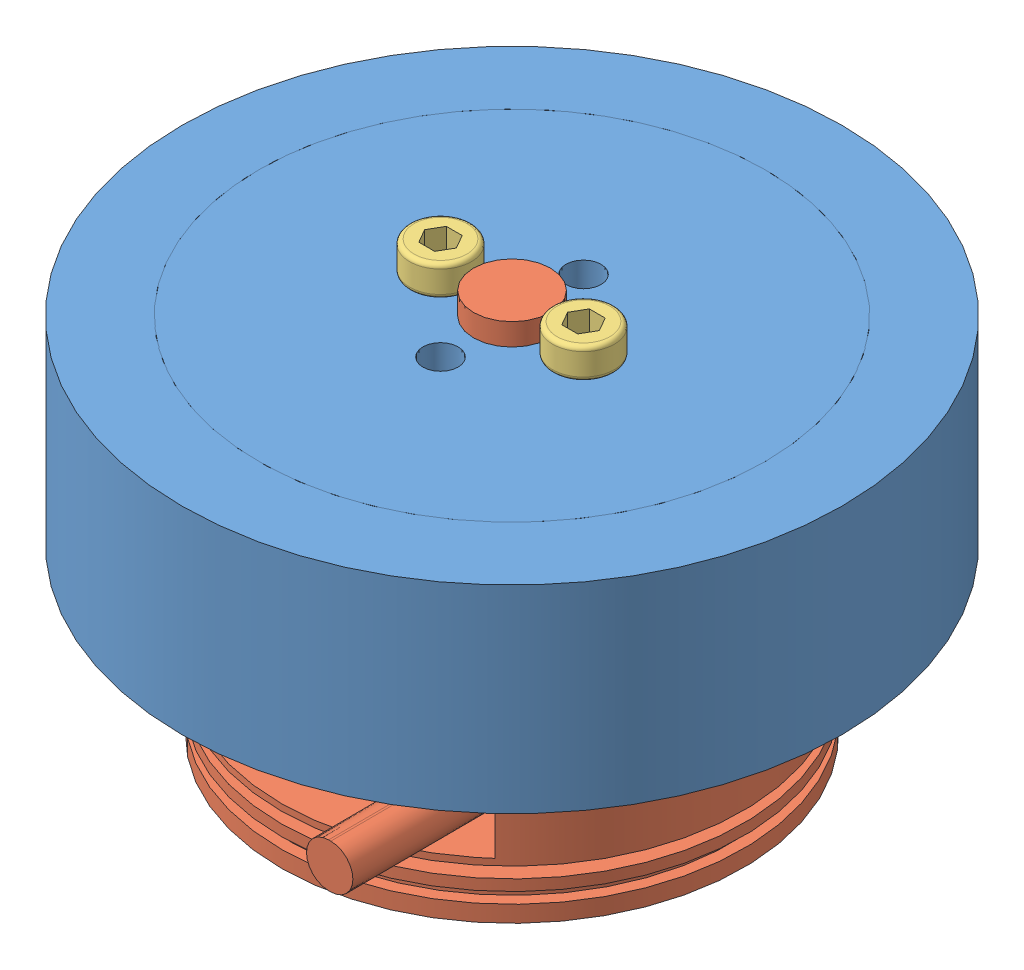
SolidWorks assembly 大弹丸发射摩擦轮, configuration 默认. Lengths in mm.
Overall size (60 99.1 60).
4 component instances, 3 part files, 6 mates.
Components (placement in the parent):
- 大弹丸发射摩擦轮-2: 大弹丸发射摩擦轮 [默认] x (-1 0 0) z (0 -1 0) size (60 60 18)
- 3508去除减速箱-2: 3508去除减速箱 [默认] at (0 -41.7 0) x (0.999992 0 -0.003984) z (0.003984 0 0.999992) size (42 98.3 47)
- 螺栓M3-6-1: 螺栓M3-6 [默认] at (-6.5 -6 0) size (5.6 8.8 5.6)
- 螺栓M3-6-2: 螺栓M3-6 [默认] at (6.5 -6 0) size (5.6 8.8 5.6)
Mates (geometry in assembly coordinates):
- 同心1: concentric aligned: cylinder of 大弹丸发射摩擦轮-2 through (0 0 0) axis (0 1 0) radius 21; cylinder of 3508去除减速箱-2 through (0 2 0) axis (0 1 0) radius 21
- 重合5: coincident anti-aligned: plane of 大弹丸发射摩擦轮-2 through (21 -3 0) normal (0 -1 0); plane of 3508去除减速箱-2 through (18.2999 -3 -0.0729) normal (0 1 0)
- 同心2: concentric anti-aligned: cylinder of 大弹丸发射摩擦轮-2 through (-6.5 -10 0) axis (0 1 0) radius 1.6; cylinder of 螺栓M3-6-1 through (-6.5 -6 0) axis (0 -1 0) radius 1.5
- 重合6: coincident anti-aligned: plane of 大弹丸发射摩擦轮-2 through (3.5 0 0) normal (0 1 0); plane of 螺栓M3-6-1 through (-8.9 0 0) normal (0 -1 0)
- 同心3: concentric anti-aligned: cylinder of 大弹丸发射摩擦轮-2 through (6.5 -10 0) axis (0 1 0) radius 1.6; cylinder of 螺栓M3-6-2 through (6.5 -6 0) axis (0 -1 0) radius 1.5
- 重合7: coincident anti-aligned: plane of 大弹丸发射摩擦轮-2 through (3.5 0 0) normal (0 1 0); plane of 螺栓M3-6-2 through (4.1 0 0) normal (0 -1 0)
